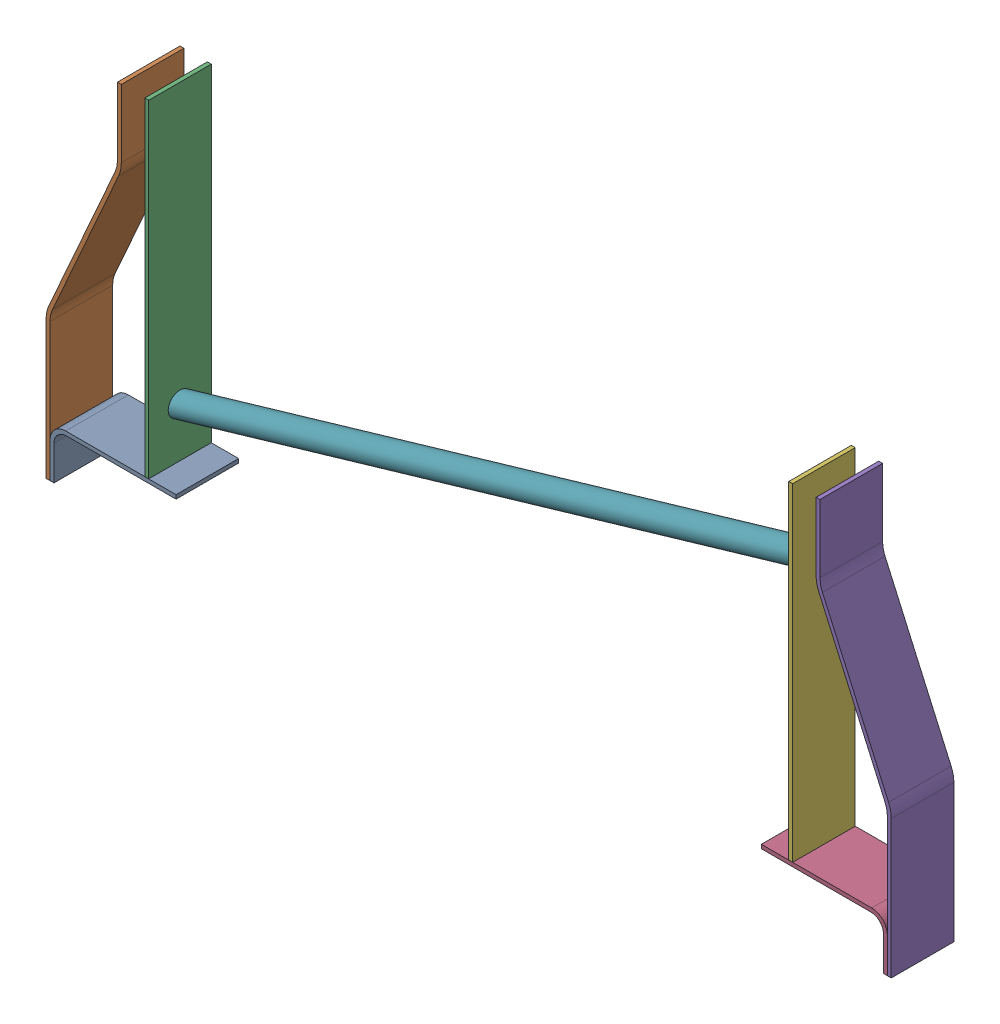
SolidWorks assembly StrutLeftAssem, configuration Default. Lengths in mm.
Overall size (1371.5 631.13 101.6).
7 component instances, 6 part files, 16 mates.
Components (placement in the parent):
- StrutLeft-1: StrutLeft [Default] at (-18.5919 113.7747 65.3035) size (204.47 82.55 101.6)
- StrutLeftBendedPiece-1: StrutLeftBendedPiece [Default] at (-24.9419 266.1747 65.3035) size (121.92 614.73 101.6)
- StrutLeftStraightPiece-1: StrutLeftStraightPiece [Default] at (135.0781 645.9047 65.3035) size (6.35 532.13 101.6)
- StrutRight-1: StrutRight [Default] at (931.2693 97.3828 65.3035) size (204.47 82.55 101.6)
- StrutRightBendedPiece-1: StrutRightBendedPiece [Default] at (1163.6793 322.2001 65.3035) size (121.92 614.73 101.6)
- StrutLeftStraightPiece-2: StrutLeftStraightPiece [Default] at (1180.1893 629.5128 65.3035) size (6.35 532.13 101.6)
- XBarLong-1: XBarLong [Default] at (141.4281 194.1017 116.1035) size (1038.86 342.87 38.1)
Mates (geometry in assembly coordinates):
- Coincident1: coincident aligned: plane of StrutLeft-1 through (-12.2419 31.2247 166.9035) normal (0 -1 0); plane of StrutLeftBendedPiece-1 through (-24.9419 31.2247 166.9035) normal (0 -1 0)
- Coincident2: coincident anti-aligned: plane of StrutLeft-1 through (-18.5919 31.2247 166.9035) normal (-1 0 0); plane of StrutLeftBendedPiece-1 through (-18.5919 31.2247 166.9035) normal (1 0 0)
- Coincident3: coincident aligned: plane of StrutLeft-1 through (8.0781 87.1047 166.9035) normal (0 0 1); plane of StrutLeftBendedPiece-1 through (27.1281 255.1281 166.9035) normal (0 0 1)
- Distance1: distance = 44.45 mm aligned: plane of StrutLeftStraightPiece-1 through (141.4281 645.9047 166.9035) normal (1 0 0); plane of StrutLeft-1 through (185.8781 113.7747 166.9035) normal (1 0 0)
- Coincident5: coincident anti-aligned: plane of StrutLeft-1 through (6.8081 113.7747 166.9035) normal (0 1 0); plane of StrutLeftStraightPiece-1 through (141.4281 113.7747 166.9035) normal (0 -1 0)
- Coincident6: coincident aligned: plane of StrutLeft-1 through (8.0781 87.1047 166.9035) normal (0 0 1); plane of StrutLeftStraightPiece-1 through (135.0781 645.9047 166.9035) normal (0 0 1)
- Coincident7: coincident anti-aligned: plane of StrutRight-1 through (1340.2093 14.8328 166.9035) normal (1 0 0); plane of StrutRightBendedPiece-1 through (1340.2093 14.8328 166.9035) normal (-1 0 0)
- Coincident8: coincident aligned: plane of StrutRight-1 through (1333.8593 14.8328 166.9035) normal (0 -1 0); plane of StrutRightBendedPiece-1 through (1346.5593 14.8328 166.9035) normal (0 -1 0)
- Coincident9: coincident aligned: plane of StrutRight-1 through (1313.5393 70.7128 166.9035) normal (0 0 1); plane of StrutRightBendedPiece-1 through (1276.7093 519.6009 166.9035) normal (0 0 1)
- Coincident10: coincident anti-aligned: plane of StrutRight-1 through (1135.7393 97.3828 166.9035) normal (0 1 0); plane of StrutLeftStraightPiece-2 through (1186.5393 97.3828 166.9035) normal (0 -1 0)
- Coincident11: coincident aligned: plane of StrutRight-1 through (1313.5393 70.7128 166.9035) normal (0 0 1); plane of StrutLeftStraightPiece-2 through (1180.1893 629.5128 166.9035) normal (0 0 1)
- Distance2: distance = 44.45 mm aligned: plane of StrutLeftStraightPiece-2 through (1180.1893 97.3828 166.9035) normal (-1 0 0); plane of StrutRight-1 through (1135.7393 97.3828 166.9035) normal (-1 0 0)
- Coincident13: coincident anti-aligned: plane of StrutLeftStraightPiece-1 through (141.4281 645.9047 166.9035) normal (1 0 0); plane of XBarLong-1 through (141.4281 194.1017 116.1035) normal (-1 0 0)
- Coincident14: coincident anti-aligned: plane of StrutLeftStraightPiece-2 through (1180.1893 97.3828 166.9035) normal (-1 0 0); plane of XBarLong-1 through (1180.1893 498.8727 116.1035) normal (1 0 0)
- Distance4: distance = 50.8 mm: plane of StrutLeftStraightPiece-1 through (135.0781 645.9047 166.9035) normal (0 0 1); point of XBarLong-1
- Distance6: distance = 50.8 mm: plane of assembly; point of XBarLong-1; plane of StrutLeftStraightPiece-2 through (1180.1893 629.5128 166.9035) normal (0 0 1)
